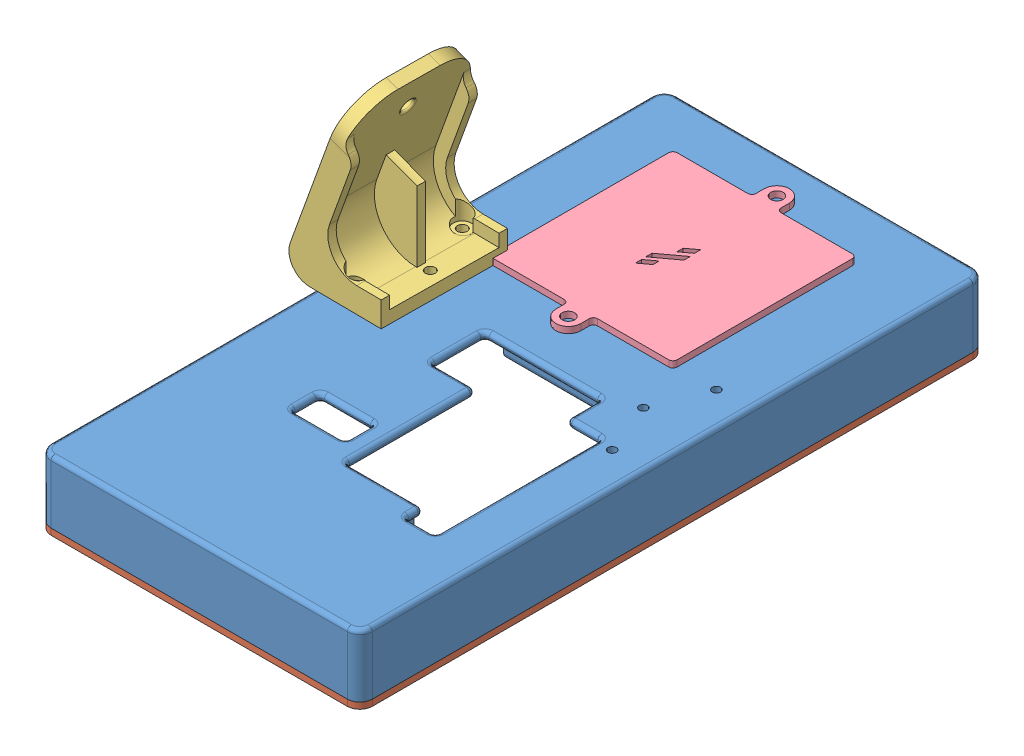
SolidWorks assembly 装配体1, configuration 默认. Lengths in mm.
Overall size (83.17 59.23 150).
4 component instances, 4 part files, 6 mates.
Components (placement in the parent):
- 零件1-1: 零件1 [默认] at (9.5672 34.9465 1301.7776) size (77 15 150)
- 零件2-1: 零件2 [默认] at (9.3182 34.9465 1377.4848) size (77 1.5 150)
- D1红米支架2-1: D1红米支架2 [默认] at (-74.8749 52.9465 -17.9679) x (0.009496 0 -0.999955) z (0 -1 0) size (30.33 22.34 42.73)
- 零件3-1: 零件3 [默认] at (-53.0106 49.9465 -29.7287) size (44 1.5 56)
Mates (geometry in assembly coordinates):
- 同心1: concentric: cylinder of assembly; cylinder of assembly; cylinder of 零件1-1 through (-109.5802 49.9465 -84.2287) axis (0 -1 0) radius 3; cylinder of 零件2-1 through (-109.5802 49.9465 -84.2287) axis (0 -1 0) radius 3
- 重合1: coincident: plane of assembly; plane of assembly; plane of 零件1-1 through (-38.5802 34.9465 59.7713) normal (0 -1 0); plane of 零件2-1 through (-38.5802 34.9465 59.7713) normal (0 1 0)
- 重合2: coincident: plane of assembly; plane of assembly; plane of 零件1-1 through (-38.5802 49.9465 59.7713) normal (0 1 0); plane of D1红米支架2-1 through (-74.8749 49.9465 -17.9679) normal (0 -1 0)
- 相切1: tangent: torus of 零件1-1; cylinder of ? through (-75.0802 55.5039 -76.7287) axis (0 -1 0) radius 1.5
- 重合3: coincident: circle of 零件1-1; cylinder of ? through (-75.0802 55.5039 -26.7287) axis (0 -1 0) radius 1.5
- 重合4: coincident: plane of assembly; plane of assembly; plane of 零件1-1 through (-38.5802 49.9465 59.7713) normal (0 1 0); plane of 零件3-1 through (-53.0106 49.9465 -29.7287) normal (0 -1 0)
